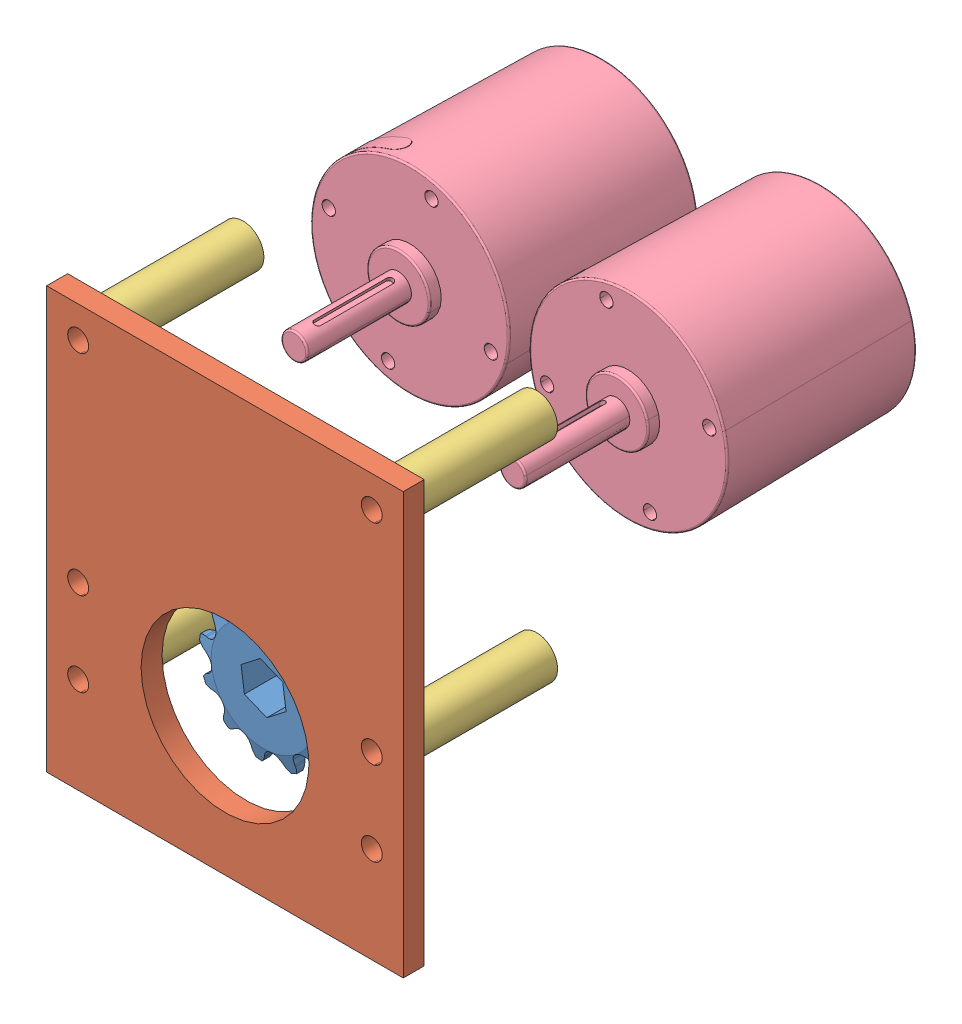
SolidWorks assembly Assembly, configuration Default. Lengths in mm.
Overall size (139.58 131.74 147.26).
11 component instances, 6 part files, 21 mates.
Components (placement in the parent):
- 2_Stage_with_Grayhill_Encoder_217-2428.STEP-1: 2_Stage_with_Grayhill_Encoder_217-2428.STEP [Default] at (44.7135 130.7865 252.4482) (suppressed, hidden, flexible)
- 12t_Steel_Double_Hub_Sprocket_35_Steel_1_2_Hex_Bore_217-5845.step-1: 12t_Steel_Double_Hub_Sprocket_35_Steel_1_2_Hex_Bore_217-5845.step [Default] at (44.7135 130.7865 284.9602) x (-0.612477 0.790488 0) z (0 0 1) size (40.72 40.72 21.35)
- Part47-1: Part47 [Default] at (44.7135 130.7865 322.9661) x (0.704215 0.709987 0) z (0 0 1) (suppressed, hidden)
- Part48-1: Part48 [Default] at (44.7135 130.7865 322.9661) x (0.704215 0.709987 0) z (0 0 1) (suppressed, hidden)
- part-1: part [Default] at (44.7135 129.394 309.4966) size (107.95 127.51 6.35)
- spacer-1: spacer [Default] at (89.1635 205.594 265.9483) x (-0.806687 0.590979 0) z (0 0 1) size (12.7 12.7 43.43)
- spacer-2: spacer [Default] at (89.1635 142.094 265.9483) x (0.727987 -0.685591 0) z (0 0 1) size (12.7 12.7 43.43)
- spacer-3: spacer [Default] at (0.2635 205.594 265.9483) x (0.886292 -0.463127 0) z (0 0 1) size (12.7 12.7 43.43)
- spacer-4: spacer [Default] at (0.2635 116.694 265.9483) x (0.973397 -0.229127 0) z (0 0 1) size (12.7 12.7 43.43)
- REV-21-1650-1: REV-21-1650 [Default] at (77.7716 182.6152 226.8323) x (0.965926 0.258819 0) z (0 0 1) size (59.98 59.98 93.25)
- REV-21-1650-2: REV-21-1650 [Default] at (11.6554 182.6152 226.8323) x (0.965926 -0.258819 0) z (0 0 1) size (59.98 59.98 93.25)
Mates (geometry in assembly coordinates):
- Concentric1: concentric aligned: circle of 2_Stage_with_Grayhill_Encoder_217-2428.STEP-1/gearbox hex-1; circle of 12t_Steel_Double_Hub_Sprocket_35_Steel_1_2_Hex_Bore_217-5845.step-1
- Parallel3: parallel anti-aligned: plane of 2_Stage_with_Grayhill_Encoder_217-2428.STEP-1/gearbox hex-1 through (38.9174 126.2956 403.1464) normal (-0.378344 -0.925665 0); plane of 12t_Steel_Double_Hub_Sprocket_35_Steel_1_2_Hex_Bore_217-5845.step-1 through (38.9058 126.2866 282.8129) normal (0.378344 0.925665 0)
- Concentric2: concentric aligned: cylinder of 2_Stage_with_Grayhill_Encoder_217-2428.STEP-1/gearbox hex-1 through (44.7135 130.7865 388.8589) axis (0 0 -1) radius 1.27; cylinder of part-1 through (44.7135 130.7865 315.8466) axis (0 0 -1) radius 25.4
- Coincident1: coincident anti-aligned: plane of 2_Stage_with_Grayhill_Encoder_217-2428.STEP-1/217-2792-001 Rev1.STEP-1/217-2790-001 Rev2.STEP-1/217-2790-003 Rev2 .STEP-1 through (44.7135 130.7865 282.8139) normal (0 0 1); plane of 12t_Steel_Double_Hub_Sprocket_35_Steel_1_2_Hex_Bore_217-5845.step-1 through (32.1693 121.0672 282.8139) normal (0 0 -1)
- Distance1: distance = 5.334 mm anti-aligned: plane of 12t_Steel_Double_Hub_Sprocket_35_Steel_1_2_Hex_Bore_217-5845.step-1 through (32.1693 121.0672 304.1626) normal (0 0 1); plane of part-1 through (44.7135 129.394 309.4966) normal (0 0 -1)
- Parallel4: parallel anti-aligned: line of 2_Stage_with_Grayhill_Encoder_217-2428.STEP-1/217-2428-002 Rev2.STEP-1 through (98.6885 205.594 252.4482) axis (0 -1 0); line of part-1 through (98.6885 87.611 309.4966) axis (0 1 0)
- Concentric3: concentric aligned: circle of part-1; circle of spacer-1
- Coincident9: coincident anti-aligned: plane of 2_Stage_with_Grayhill_Encoder_217-2428.STEP-1/217-2428-002 Rev2.STEP-1 through (89.1635 205.594 265.9483) normal (0 0 1); plane of spacer-1 through (89.1635 205.594 265.9483) normal (0 0 -1)
- Concentric4: concentric aligned: circle of part-1; circle of spacer-3
- Coincident12: coincident anti-aligned: plane of 2_Stage_with_Grayhill_Encoder_217-2428.STEP-1/217-2428-002 Rev2.STEP-1 through (0.2635 205.594 265.9483) normal (0 0 1); plane of spacer-3 through (0.2635 205.594 265.9483) normal (0 0 -1)
- Concentric5: concentric aligned: circle of part-1; circle of spacer-2
- Coincident15: coincident anti-aligned: plane of 2_Stage_with_Grayhill_Encoder_217-2428.STEP-1/217-2428-002 Rev2.STEP-1 through (89.1635 142.094 265.9483) normal (0 0 1); plane of spacer-2 through (89.1635 142.094 265.9483) normal (0 0 -1)
- Concentric6: concentric aligned: circle of part-1; circle of spacer-4
- Coincident17: coincident anti-aligned: plane of 2_Stage_with_Grayhill_Encoder_217-2428.STEP-1/217-2428-002 Rev2.STEP-1 through (0.2635 116.694 265.9483) normal (0 0 1); plane of spacer-4 through (0.2635 116.694 265.9483) normal (0 0 -1)
- Concentric7: concentric anti-aligned: cylinder of 2_Stage_with_Grayhill_Encoder_217-2428.STEP-1/217-2428-002 Rev2.STEP-1 through (89.1635 205.594 263.4083) axis (0 0 1) radius 3.302; cylinder of part-1 through (89.1635 205.594 315.8466) axis (0 0 -1) radius 3.175
- Concentric8: concentric aligned: cylinder of 2_Stage_with_Grayhill_Encoder_217-2428.STEP-1/217-2428-001 Rev1.STEP-1 through (77.7716 182.6152 230.0073) axis (0 0 -1) radius 9.5885; cylinder of REV-21-1650-1 through (77.7716 182.6152 308.146) axis (0 0 -1) radius 4
- Concentric9: concentric aligned: cylinder of 2_Stage_with_Grayhill_Encoder_217-2428.STEP-1/SBS1_SBS1032-0500ZC.STEP-4 through (71.1976 207.1497 232.5727) axis (0 0 1) radius 2.413; cylinder of REV-21-1650-1 through (71.1976 207.1497 226.8323) axis (0 0 1) radius 2.0193
- Coincident18: coincident anti-aligned: plane of 2_Stage_with_Grayhill_Encoder_217-2428.STEP-1/217-2428-001 Rev1.STEP-1 through (89.1635 205.594 226.8323) normal (0 0 -1); plane of REV-21-1650-1 through (77.7716 182.6152 226.8323) normal (0 0 1)
- Concentric10: concentric anti-aligned: circle of 2_Stage_with_Grayhill_Encoder_217-2428.STEP-1/217-2428-001 Rev1.STEP-1; circle of REV-21-1650-2
- Concentric11: concentric aligned: circle of 2_Stage_with_Grayhill_Encoder_217-2428.STEP-1/SBS1_SBS1032-0500ZC.STEP-2; circle of REV-21-1650-2
- Coincident19: coincident anti-aligned: plane of 2_Stage_with_Grayhill_Encoder_217-2428.STEP-1/217-2428-001 Rev1.STEP-1 through (89.1635 205.594 226.8323) normal (0 0 -1); plane of REV-21-1650-2 through (11.6554 182.6152 226.8323) normal (0 0 1)
